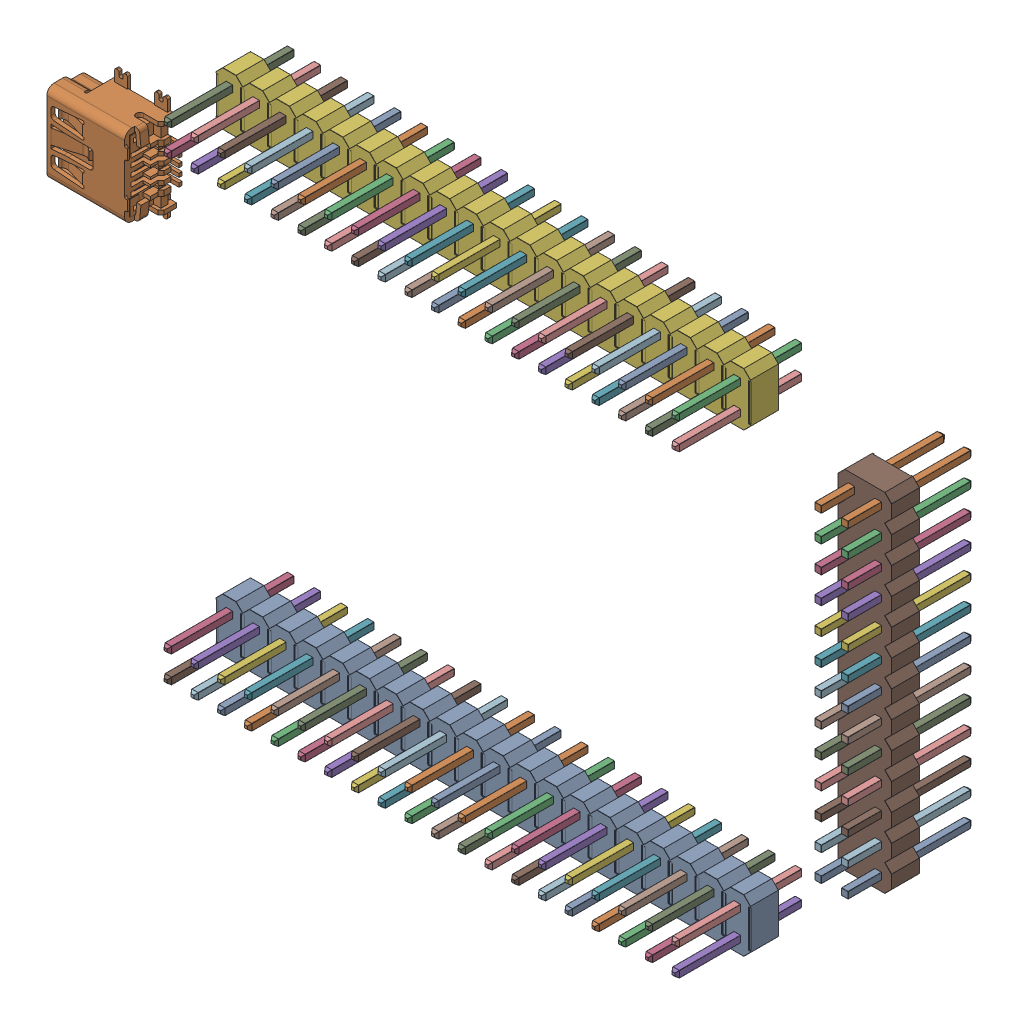
SolidWorks assembly Connectors, configuration Default. Lengths in mm.
Overall size (74.72 48.4 19.03).
116 component instances, 69 part files, 0 mates.
Components (placement in the parent):
- 2x20 Male 0.1in Header Connector-1: 2x20 Male 0.1in Header Connector [Default] at (1.53 -21.59 1.6002) size (50.8 5.09 11.89)
  - Plastic-1: Plastic [Default] at origin size (50.8 5.09 2.67)
  - Pins-1: Pins [Default] at origin size (48.9 3.18 11.89)
    - Pins_34-1: Pins_34 [Default] at origin size (0.64 0.64 11.89)
    - Pins_30-1: Pins_30 [Default] at origin size (0.64 0.64 11.89)
    - Pins_33-1: Pins_33 [Default] at origin size (0.64 0.64 11.89)
    - Pins_24-1: Pins_24 [Default] at origin size (0.64 0.64 11.89)
    - Pins_10-1: Pins_10 [Default] at origin size (0.64 0.64 11.89)
    - Pins_39-1: Pins_39 [Default] at origin size (0.64 0.64 11.89)
    - Pins_6-1: Pins_6 [Default] at origin size (0.64 0.64 11.89)
    - Pins_2-1: Pins_2 [Default] at origin size (0.64 0.64 11.89)
    - Pins_28-1: Pins_28 [Default] at origin size (0.64 0.64 11.89)
    - Pins_25-1: Pins_25 [Default] at origin size (0.64 0.64 11.89)
    - Pins_12-1: Pins_12 [Default] at origin size (0.64 0.64 11.89)
    - Pins_16-1: Pins_16 [Default] at origin size (0.64 0.64 11.89)
    - Pins-1: Pins [Default] at origin size (0.64 0.64 11.89)
    - Pins_40-1: Pins_40 [Default] at origin size (0.64 0.64 11.89)
    - Pins_18-1: Pins_18 [Default] at origin size (0.64 0.64 11.89)
    - Pins_32-1: Pins_32 [Default] at origin size (0.64 0.64 11.89)
    - Pins_15-1: Pins_15 [Default] at origin size (0.64 0.64 11.89)
    - Pins_35-1: Pins_35 [Default] at origin size (0.64 0.64 11.89)
    - Pins_7-1: Pins_7 [Default] at origin size (0.64 0.64 11.89)
    - Pins_20-1: Pins_20 [Default] at origin size (0.64 0.64 11.89)
    - Pins_27-1: Pins_27 [Default] at origin size (0.64 0.64 11.89)
    - Pins_29-1: Pins_29 [Default] at origin size (0.64 0.64 11.89)
    - Pins_19-1: Pins_19 [Default] at origin size (0.64 0.64 11.89)
    - Pins_37-1: Pins_37 [Default] at origin size (0.64 0.64 11.89)
    - Pins_38-1: Pins_38 [Default] at origin size (0.64 0.64 11.89)
    - Pins_23-1: Pins_23 [Default] at origin size (0.64 0.64 11.89)
    - Pins_4-1: Pins_4 [Default] at origin size (0.64 0.64 11.89)
    - Pins_36-1: Pins_36 [Default] at origin size (0.64 0.64 11.89)
    - Pins_26-1: Pins_26 [Default] at origin size (0.64 0.64 11.89)
    - Pins_8-1: Pins_8 [Default] at origin size (0.64 0.64 11.89)
    - Pins_9-1: Pins_9 [Default] at origin size (0.64 0.64 11.89)
    - Pins_13-1: Pins_13 [Default] at origin size (0.64 0.64 11.89)
    - Pins_3-1: Pins_3 [Default] at origin size (0.64 0.64 11.89)
    - Pins_5-1: Pins_5 [Default] at origin size (0.64 0.64 11.89)
    - Pins_31-1: Pins_31 [Default] at origin size (0.64 0.64 11.89)
    - Pins_21-1: Pins_21 [Default] at origin size (0.64 0.64 11.89)
    - Pins_11-1: Pins_11 [Default] at origin size (0.64 0.64 11.89)
    - Pins_14-1: Pins_14 [Default] at origin size (0.64 0.64 11.89)
    - Pins_17-1: Pins_17 [Default] at origin size (0.64 0.64 11.89)
    - Pins_22-1: Pins_22 [Default] at origin size (0.64 0.64 11.89)
- 2x20 Male 0.1in Header Connector_1-1: 2x20 Male 0.1in Header Connector_1 [Default] at (1.53 21.72 1.6002) size (50.8 5.09 11.89)
  - Plastic-1: Plastic [Default] at origin size (50.8 5.09 2.67)
  - Pins-1: Pins [Default] at origin size (48.9 3.18 11.89)
    - Pins_34-1: Pins_34 [Default] at origin size (0.64 0.64 11.89)
    - Pins_30-1: Pins_30 [Default] at origin size (0.64 0.64 11.89)
    - Pins_33-1: Pins_33 [Default] at origin size (0.64 0.64 11.89)
    - Pins_24-1: Pins_24 [Default] at origin size (0.64 0.64 11.89)
    - Pins_10-1: Pins_10 [Default] at origin size (0.64 0.64 11.89)
    - Pins_39-1: Pins_39 [Default] at origin size (0.64 0.64 11.89)
    - Pins_6-1: Pins_6 [Default] at origin size (0.64 0.64 11.89)
    - Pins_2-1: Pins_2 [Default] at origin size (0.64 0.64 11.89)
    - Pins_28-1: Pins_28 [Default] at origin size (0.64 0.64 11.89)
    - Pins_25-1: Pins_25 [Default] at origin size (0.64 0.64 11.89)
    - Pins_12-1: Pins_12 [Default] at origin size (0.64 0.64 11.89)
    - Pins_16-1: Pins_16 [Default] at origin size (0.64 0.64 11.89)
    - Pins-1: Pins [Default] at origin size (0.64 0.64 11.89)
    - Pins_40-1: Pins_40 [Default] at origin size (0.64 0.64 11.89)
    - Pins_18-1: Pins_18 [Default] at origin size (0.64 0.64 11.89)
    - Pins_32-1: Pins_32 [Default] at origin size (0.64 0.64 11.89)
    - Pins_15-1: Pins_15 [Default] at origin size (0.64 0.64 11.89)
    - Pins_35-1: Pins_35 [Default] at origin size (0.64 0.64 11.89)
    - Pins_7-1: Pins_7 [Default] at origin size (0.64 0.64 11.89)
    - Pins_20-1: Pins_20 [Default] at origin size (0.64 0.64 11.89)
    - Pins_27-1: Pins_27 [Default] at origin size (0.64 0.64 11.89)
    - Pins_29-1: Pins_29 [Default] at origin size (0.64 0.64 11.89)
    - Pins_19-1: Pins_19 [Default] at origin size (0.64 0.64 11.89)
    - Pins_37-1: Pins_37 [Default] at origin size (0.64 0.64 11.89)
    - Pins_38-1: Pins_38 [Default] at origin size (0.64 0.64 11.89)
    - Pins_23-1: Pins_23 [Default] at origin size (0.64 0.64 11.89)
    - Pins_4-1: Pins_4 [Default] at origin size (0.64 0.64 11.89)
    - Pins_36-1: Pins_36 [Default] at origin size (0.64 0.64 11.89)
    - Pins_26-1: Pins_26 [Default] at origin size (0.64 0.64 11.89)
    - Pins_8-1: Pins_8 [Default] at origin size (0.64 0.64 11.89)
    - Pins_9-1: Pins_9 [Default] at origin size (0.64 0.64 11.89)
    - Pins_13-1: Pins_13 [Default] at origin size (0.64 0.64 11.89)
    - Pins_3-1: Pins_3 [Default] at origin size (0.64 0.64 11.89)
    - Pins_5-1: Pins_5 [Default] at origin size (0.64 0.64 11.89)
    - Pins_31-1: Pins_31 [Default] at origin size (0.64 0.64 11.89)
    - Pins_21-1: Pins_21 [Default] at origin size (0.64 0.64 11.89)
    - Pins_11-1: Pins_11 [Default] at origin size (0.64 0.64 11.89)
    - Pins_14-1: Pins_14 [Default] at origin size (0.64 0.64 11.89)
    - Pins_17-1: Pins_17 [Default] at origin size (0.64 0.64 11.89)
    - Pins_22-1: Pins_22 [Default] at origin size (0.64 0.64 11.89)
- 2x13 Male 0.1in Header Connector-1: 2x13 Male 0.1in Header Connector [Default] at (34.8 0 0.0002) x (0 -1 0) z (0 0 -1) size (33.02 5.09 11.89)
  - Plastic_1-1: Plastic_1 [Default] at origin size (33.02 5.09 2.67)
  - Pins_1-1: Pins_1 [Default] at origin size (31.12 3.18 11.89)
    - Pins_1_16-1: Pins_1_16 [Default] at origin size (0.64 0.64 11.89)
    - Pins_1_2-1: Pins_1_2 [Default] at origin size (0.64 0.64 11.89)
    - Pins_1_24-1: Pins_1_24 [Default] at origin size (0.64 0.64 11.89)
    - Pins_1_19-1: Pins_1_19 [Default] at origin size (0.64 0.64 11.89)
    - Pins_1_12-1: Pins_1_12 [Default] at origin size (0.64 0.64 11.89)
    - Pins_1_7-1: Pins_1_7 [Default] at origin size (0.64 0.64 11.89)
    - Pins_1_5-1: Pins_1_5 [Default] at origin size (0.64 0.64 11.89)
    - Pins_1_13-1: Pins_1_13 [Default] at origin size (0.64 0.64 11.89)
    - Pins_1_8-1: Pins_1_8 [Default] at origin size (0.64 0.64 11.89)
    - Pins_1_3-1: Pins_1_3 [Default] at origin size (0.64 0.64 11.89)
    - Pins_1_22-1: Pins_1_22 [Default] at origin size (0.64 0.64 11.89)
    - Pins_1_18-1: Pins_1_18 [Default] at origin size (0.64 0.64 11.89)
    - Pins_1_20-1: Pins_1_20 [Default] at origin size (0.64 0.64 11.89)
    - Pins_1_23-1: Pins_1_23 [Default] at origin size (0.64 0.64 11.89)
    - Pins_1_25-1: Pins_1_25 [Default] at origin size (0.64 0.64 11.89)
    - Pins_1_26-1: Pins_1_26 [Default] at origin size (0.64 0.64 11.89)
    - Pins_1_10-1: Pins_1_10 [Default] at origin size (0.64 0.64 11.89)
    - Pins_1_15-1: Pins_1_15 [Default] at origin size (0.64 0.64 11.89)
    - Pins_1_14-1: Pins_1_14 [Default] at origin size (0.64 0.64 11.89)
    - Pins_1-1: Pins_1 [Default] at origin size (0.64 0.64 11.89)
    - Pins_1_4-1: Pins_1_4 [Default] at origin size (0.64 0.64 11.89)
    - Pins_1_21-1: Pins_1_21 [Default] at origin size (0.64 0.64 11.89)
    - Pins_1_6-1: Pins_1_6 [Default] at origin size (0.64 0.64 11.89)
    - Pins_1_11-1: Pins_1_11 [Default] at origin size (0.64 0.64 11.89)
    - Pins_1_9-1: Pins_1_9 [Default] at origin size (0.64 0.64 11.89)
    - Pins_1_17-1: Pins_1_17 [Default] at origin size (0.64 0.64 11.89)
- USB_Mini_B_SMD_buchse-1: USB_Mini_B_SMD_buchse [Default] at (-37.9777 11.749 3.6149) x (0 -1 0) z (-1 0 0) size (10 3.97 8.9)
